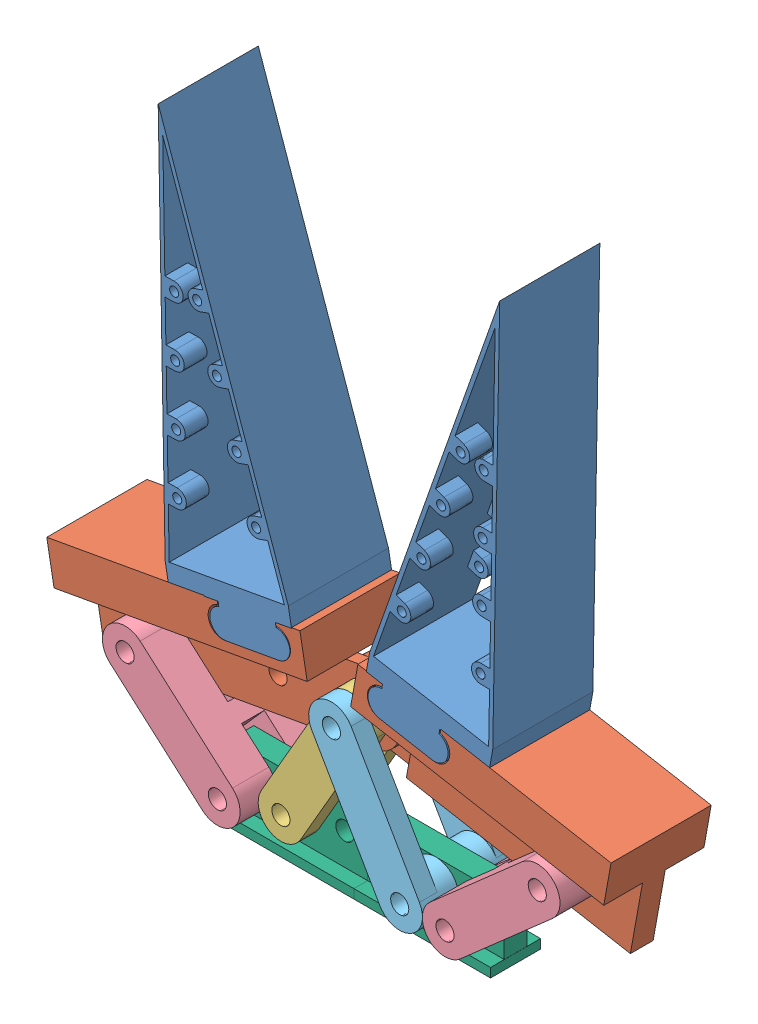
SolidWorks assembly sw-hand-open, configuration Default. Lengths in mm.
Overall size (123.95 137.74 22).
11 component instances, 6 part files, 19 mates.
Components (placement in the parent):
- Gripper-2: Gripper [Default] at (42.86 52.4832 62.323) x (0.984189 -0.177124 0) z (0 0 1) size (27.5 95.86 22)
- Platte-2: Platte [Default] at (51.9897 3.3313 53.823) x (0.984189 -0.177124 0) z (0.177124 0.984189 0) size (67.5 22 24)
- Platte-3: Platte [Default] at (28.5522 3.3313 48.823) x (-0.984189 -0.177124 0) z (-0.177124 0.984189 0) size (67.5 22 24)
- Gripper-3: Gripper [Default] at (37.6818 52.4832 40.323) x (-0.984189 -0.177124 0) z (0 0 -1) size (27.5 95.86 22)
- Arm2-1: Arm2 [Default] at (62.6559 1.4178 44.873) x (0.5 0.866025 0) z (-0.866025 0.5 0) size (40 13 10)
- Arm-1: Arm [Default] at (33.1636 44.7993 61.823) x (-0.75084 0.660484 0) z (-0.660484 -0.75084 0) size (37 21 10)
- Arm1-1: Arm1 [Default] at (82.2814 38.5965 40.973) x (-0.5 0.866025 0) z (-0.866025 -0.5 0) size (40 8 10)
- Arm1-2: Arm1 [Default] at (17.886 1.4178 61.773) x (-0.5 0.866025 0) z (0.866025 0.5 0) size (40 8 10)
- Arm-2: Arm [Default] at (96.4902 -11.0312 61.823) x (0.75084 0.660484 0) z (-0.660484 0.75084 0) size (37 21 10)
- Schiene-1: Schiene [Default] at (47.4422 -6.9666 53.823) x (1 0 0) z (0 1 0) size (30 11 14.02)
- Schiene-2: Schiene [Default] at (17.4422 -6.9666 53.823) x (1 0 0) z (0 1 0) size (30 11 14.02)
Mates (geometry in assembly coordinates):
- Coincident8: coincident aligned: plane of Gripper-2 through (63.4482 45.533 62.323) normal (0 0 1); plane of Platte-2 through (102.2448 42.615 62.323) normal (0 0 1)
- Coincident10: coincident anti-aligned: plane of Gripper-2 through (51.3034 44.6704 40.323) normal (-0.177124 -0.984189 0); plane of Platte-2 through (51.3034 44.6704 -12.6186) normal (0.177124 0.984189 0)
- Coincident11: coincident aligned: line of Gripper-2 through (51.3034 44.6704 40.323) axis (0 0 1); line of Platte-2 through (51.3034 44.6704 40.323) axis (0 0 1)
- Coincident12: coincident anti-aligned: circle of Platte-2; circle of Platte-3
- Coincident13: coincident aligned: plane of Platte-3 through (-21.7029 42.615 40.323) normal (0 0 -1); plane of Gripper-3 through (17.0937 45.533 40.323) normal (0 0 -1)
- Coincident14: coincident aligned: line of Platte-3 through (17.4282 42.545 40.323) axis (0.984189 0.177124 0); line of Gripper-3 through (17.625 42.5804 40.323) axis (0.984189 0.177124 0)
- Coincident15: coincident aligned: line of Platte-3 through (29.2385 44.6704 62.323) axis (0 0 -1); line of Gripper-3 through (29.2385 44.6704 62.323) axis (0 0 -1)
- Coincident16: coincident aligned: circle of Platte-2; circle of Arm2-1
- Coincident17: coincident aligned: circle of Platte-3; circle of Arm-1
- Coincident18: coincident aligned: circle of Arm2-1; circle of Arm1-1
- Coincident19: coincident anti-aligned: circle of Arm2-1; circle of Arm1-2
- Coincident20: coincident anti-aligned: circle of Platte-2; circle of Arm-2
- Concentric3: concentric aligned: circle of Arm-2; circle of Schiene-1
- Concentric4: concentric aligned: cylinder of Arm1-1 through (55.2709 11.0226 40.973) axis (0 0 1) radius 2; cylinder of Schiene-1 through (55.2709 11.0226 21.1274) axis (0 0 1) radius 2
- Concentric5: concentric anti-aligned: cylinder of Arm1-2 through (55.2709 11.0226 61.773) axis (0 0 -1) radius 2; cylinder of Schiene-1 through (55.2709 11.0226 21.1274) axis (0 0 1) radius 2
- Coincident22: coincident anti-aligned: plane of Arm-2 through (87.0798 -21.34 48.823) normal (0 0 1); plane of Schiene-1 through (47.4422 -6.9666 48.823) normal (0 0 -1)
- Coincident23: coincident anti-aligned: plane of Arm-1 through (34.8273 45.3666 53.823) normal (0 0 -1); plane of Schiene-2 through (17.4422 -6.9666 53.823) normal (0 0 1)
- Concentric8: concentric anti-aligned: cylinder of Arm-1 through (15.2709 11.0226 61.823) axis (0 0 -1) radius 2; cylinder of Schiene-2 through (15.2709 11.0226 21.1274) axis (0 0 1) radius 2
- Concentric9: concentric aligned: cylinder of Arm2-1 through (25.2709 11.0226 44.873) axis (0 0 1) radius 2; cylinder of Schiene-2 through (25.2709 11.0226 21.1274) axis (0 0 1) radius 2
